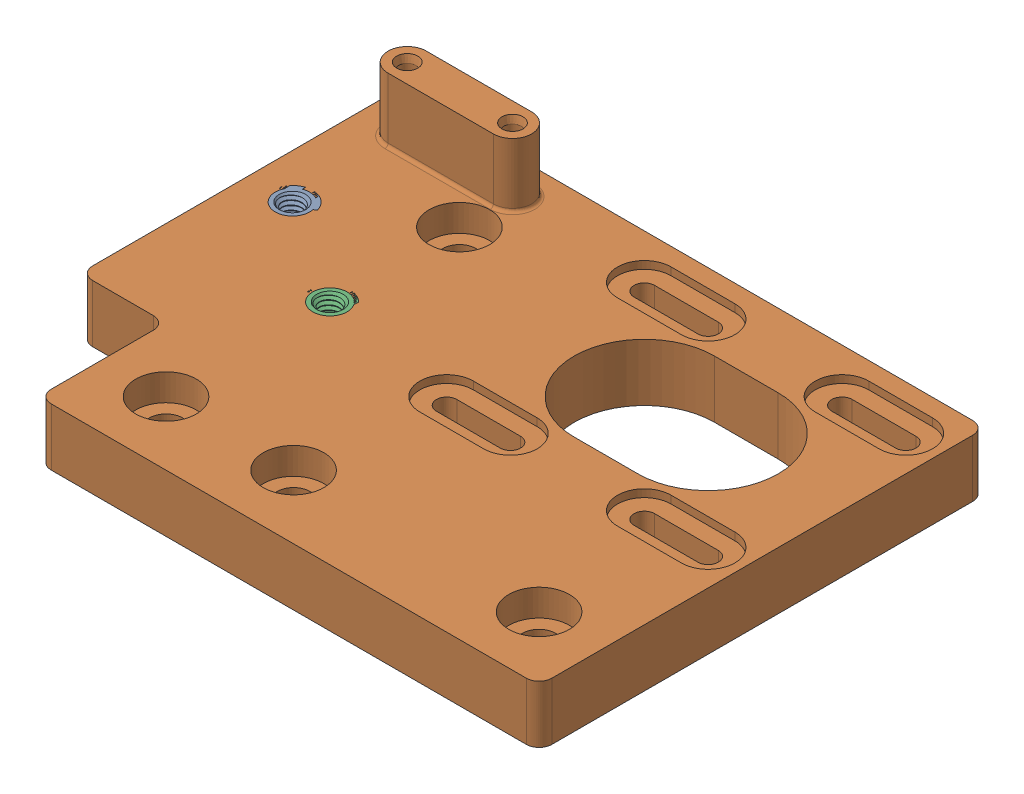
SolidWorks assembly left_motor_plate_with_inserts, configuration Default. Lengths in mm.
Overall size (92 19 70).
3 component instances, 2 part files, 0 mates.
Components (placement in the parent):
- m4_heat_set_insert_long_94180A353_94180A353-1: m4_heat_set_insert_long_94180A353_94180A353 [Default] at (-81.429 393.0105 -31.0093) size (6.35 8 6.35)
- motor_corner_bracket_Left Motor Corner Bracket-1: motor_corner_bracket_Left Motor Corner Bracket [Default] at (-74.929 384.0105 15.3157) size (92 19 70)
- m4_heat_set_insert_long_94180A353_94180A353-2: m4_heat_set_insert_long_94180A353_94180A353 [Default] at (-64.929 393.0105 -20.3843) size (6.35 8 6.35)
